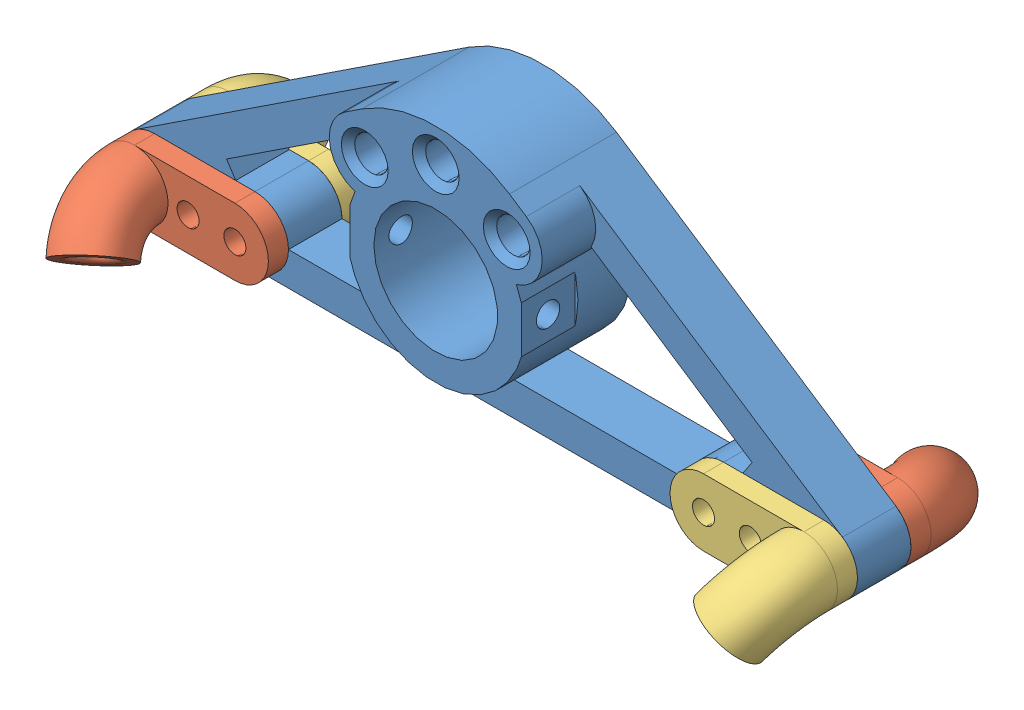
SolidWorks assembly assem_shoulder, configuration left. Lengths in mm.
Overall size (110 42.64 39.98).
5 component instances, 3 part files, 12 mates.
Components (placement in the parent):
- wire_root_curve-1: wire_root_curve [ﾃﾞﾌｫﾙﾄ] at origin size (110 40 16)
- wire_root_curve_support-1: wire_root_curve_support [ﾃﾞﾌｫﾙﾄ] at (-50 -15 11) size (25 12.64 15.99)
- wire_root_curve_support_mirror-1: wire_root_curve_support_mirror [ﾃﾞﾌｫﾙﾄ] at (50 -15 5) x (-1 0 0) z (0 0 -1) size (25 12.64 15.99)
- wire_root_curve_support-2: wire_root_curve_support [45] at (50 -15 -3) x (-1 0 0) z (0 0 -1) size (25 12.5 15.99)
- wire_root_curve_support_mirror-2: wire_root_curve_support_mirror [76] at (-50 -15 3) size (25 12.37 15.99)
Mates (geometry in assembly coordinates):
- 同心円1: concentric aligned: cylinder of wire_root_curve-1 through (-35 -15 0) axis (0 0 1) radius 1.65; cylinder of wire_root_curve_support-1 through (-35 -15 8) axis (0 0 1) radius 1.65
- 同心円2: concentric aligned: cylinder of wire_root_curve-1 through (-42 -15 0) axis (0 0 1) radius 1.65; cylinder of wire_root_curve_support-1 through (-42 -15 8) axis (0 0 1) radius 1.65
- 一致1: coincident anti-aligned: plane of wire_root_curve-1 through (50 -15 8) normal (0 0 1); plane of wire_root_curve_support-1 through (-50 -15 8) normal (0 0 -1)
- 同心円3: concentric aligned: cylinder of wire_root_curve-1 through (35 -15 0) axis (0 0 1) radius 1.65; cylinder of wire_root_curve_support_mirror-1 through (35 -15 8) axis (0 0 1) radius 1.65
- 同心円4: concentric aligned: cylinder of wire_root_curve-1 through (42 -15 0) axis (0 0 1) radius 1.65; cylinder of wire_root_curve_support_mirror-1 through (42 -15 8) axis (0 0 1) radius 1.65
- 一致2: coincident anti-aligned: plane of wire_root_curve-1 through (50 -15 8) normal (0 0 1); plane of wire_root_curve_support_mirror-1 through (50 -15 8) normal (0 0 -1)
- 同心円5: concentric anti-aligned: cylinder of wire_root_curve-1 through (42 -15 0) axis (0 0 1) radius 1.65; cylinder of wire_root_curve_support-2 through (42 -15 0) axis (0 0 -1) radius 1.65
- 同心円6: concentric anti-aligned: cylinder of wire_root_curve-1 through (35 -15 0) axis (0 0 1) radius 1.65; cylinder of wire_root_curve_support-2 through (35 -15 0) axis (0 0 -1) radius 1.65
- 一致3: coincident anti-aligned: plane of wire_root_curve-1 through (50 -15 0) normal (0 0 -1); plane of wire_root_curve_support-2 through (50 -15 0) normal (0 0 1)
- 同心円7: concentric anti-aligned: cylinder of wire_root_curve-1 through (-35 -15 0) axis (0 0 1) radius 1.65; cylinder of wire_root_curve_support_mirror-2 through (-35 -15 0) axis (0 0 -1) radius 1.65
- 同心円8: concentric anti-aligned: cylinder of wire_root_curve-1 through (-42 -15 0) axis (0 0 1) radius 1.65; cylinder of wire_root_curve_support_mirror-2 through (-42 -15 0) axis (0 0 -1) radius 1.65
- 一致5: coincident anti-aligned: plane of wire_root_curve-1 through (50 -15 0) normal (0 0 -1); plane of wire_root_curve_support_mirror-2 through (-50 -15 0) normal (0 0 1)
